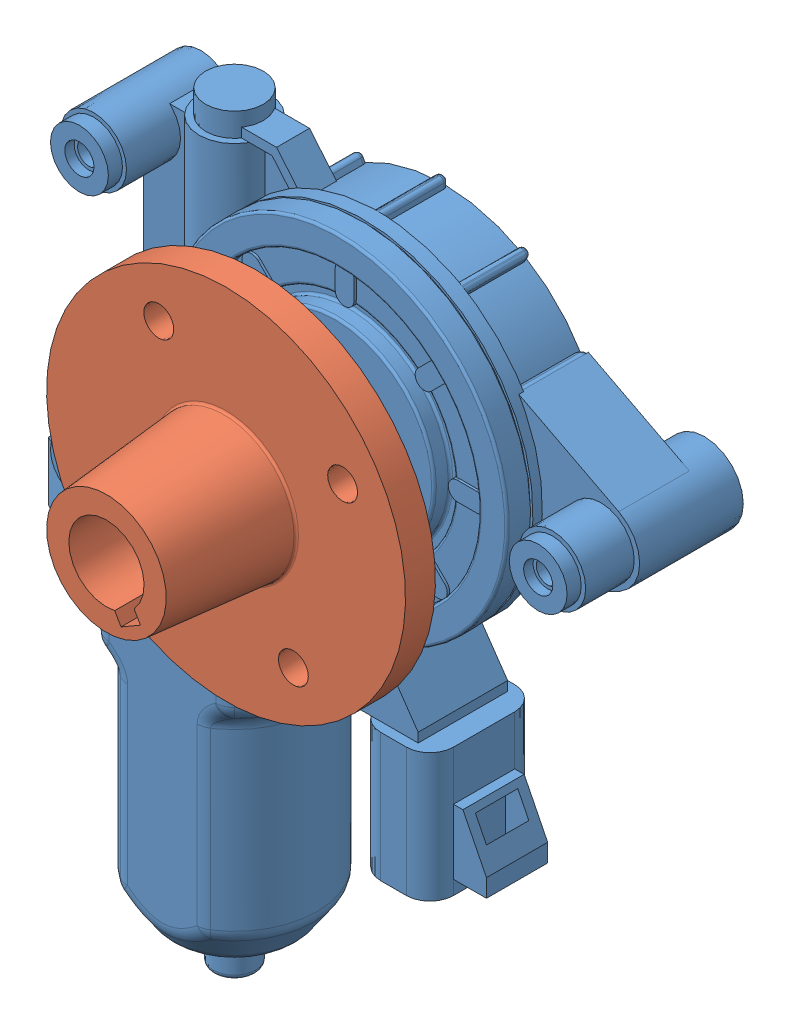
SolidWorks assembly puller, configuration Default. Lengths in mm.
Overall size (120.53 173.05 55.5).
3 component instances, 2 part files, 0 mates.
Components (placement in the parent):
- Window Motor Right with adapter-1: Window Motor Right with adapter [Default] at (8.6515 113.6079 157.0704) size (120.53 173.05 55.5)
  - ND Motor Right-1: ND Motor Right [Default] at origin size (120.53 161 55.5)
  - nippondensogearcoupler2-1: nippondensogearcoupler2 [Default] at (0 0 25.489) x (-0.866025 -0.5 0) z (0 0 -1) size (76.2 76.2 19.05)
